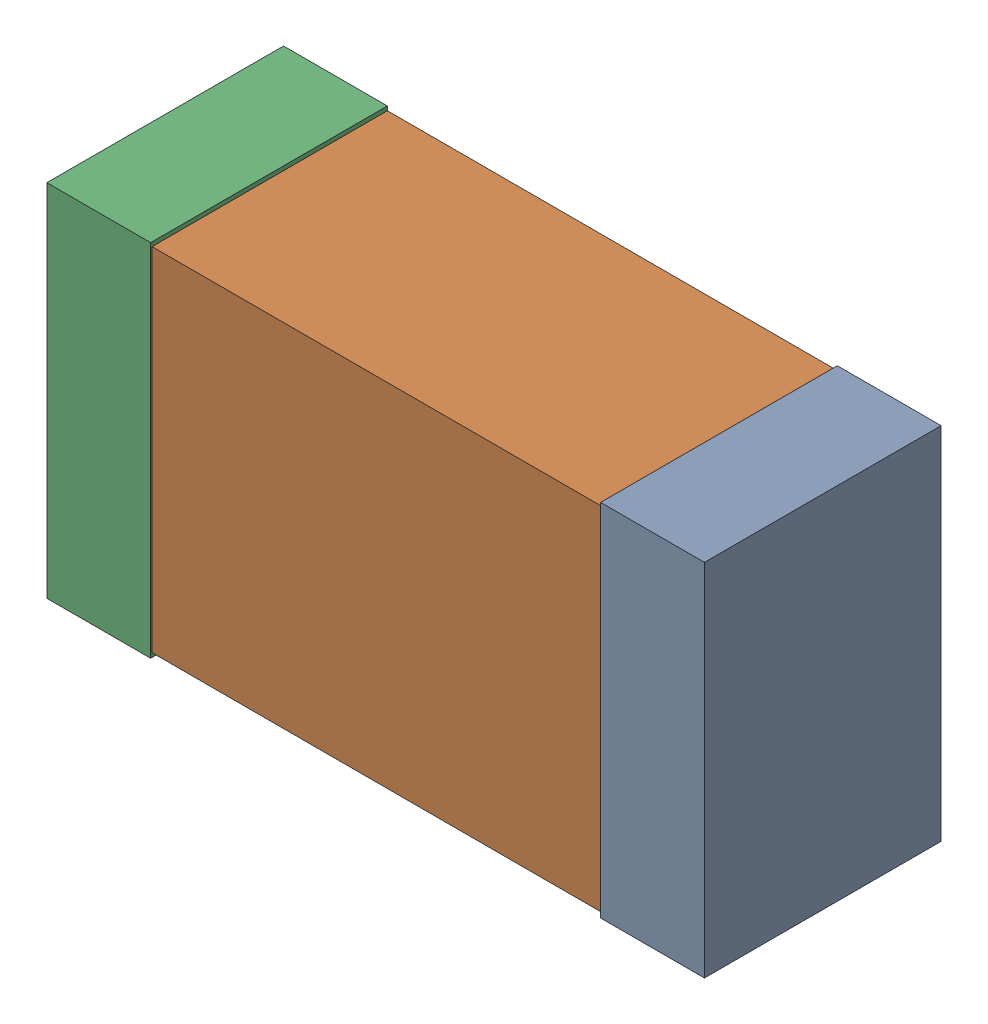
SolidWorks assembly 10kKanaloa_v2.0.0_Power, configuration Default. Lengths in mm.
Overall size (2.38 1.3 0.85).
6 component instances, 2 part files, 0 mates.
Components (placement in the parent):
- 352877648-1: 352877648 [Default] at (144.1428 88.1554 0) size (0.38 1.3 0.85)
  - Extruded_14-1: Extruded_14 [Default] at origin size (0.38 1.3 0.85)
- 352877392-1: 352877392 [Default] at (143.1428 88.1554 0) size (2.2 1.27 0.85)
  - Extruded_15-1: Extruded_15 [Default] at origin size (2.2 1.27 0.85)
- 352877648-2: 352877648 [Default] at (142.1428 88.1554 0) size (0.38 1.3 0.85)
  - Extruded_14-1: Extruded_14 [Default] at origin size (0.38 1.3 0.85)
